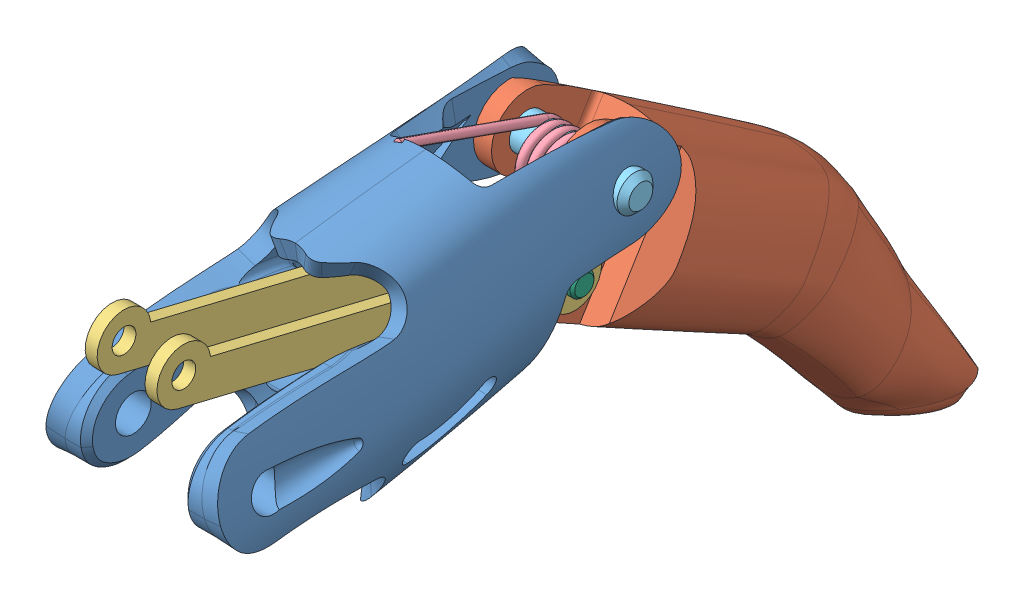
SolidWorks assembly 02-001, configuration 默认. Lengths in mm.
Overall size (17.27 43.69 77.23).
7 component instances, 6 part files, 12 mates.
Components (placement in the parent):
- 01-001-02-1: 01-001-02 [默认] at (7.8667 16.5149 53.1007) x (1 0 0) z (0 -0.162391 0.986726) size (17.27 19.24 40.8)
- 01-002-1: 01-002 [默认] at (7.8667 22.8014 23.7438) x (1 0 0) z (0 0.522694 0.85252) size (12.29 17.46 47.7)
- 01-004-1: 01-004 [默认] at (4.8667 17.742 21.4533) x (-1 0 0) z (0 -0.234701 -0.972068) size (1 6 38.5)
- 01-004-2: 01-004 [默认] at (9.8667 17.742 21.4533) x (-1 0 0) z (0 -0.234701 -0.972068) size (1 6 38.5)
- 01-009-1: 01-009 [默认] at (6.6088 23.9815 18.3511) x (1 0 0) z (0 -0.95607 0.293137) size (5.44 18.26 4.7)
- 01-035-1: 01-035 [默认] at (0.8667 24.547 17.9816) x (0 -0.984187 0.177132) z (-1 0 0) size (3 3 14)
- 01-036-1: 01-036 [默认] at (12.8667 17.2726 19.5091) x (0 -0.458162 -0.888869) z (1 0 0) size (2 2 7.6)
Mates (geometry in assembly coordinates):
- Coincident1: coincident anti-aligned: plane of 01-002-1 through (5.8667 21.8245 20.2373) normal (-1 0 0); plane of 01-004-1 through (5.8667 17.742 21.4533) normal (1 0 0)
- Coincident2: coincident anti-aligned: plane of 01-002-1 through (9.8667 21.8245 20.2373) normal (1 0 0); plane of 01-004-2 through (9.8667 17.742 21.4533) normal (-1 0 0)
- Width1: width anti-aligned: plane of 01-036-1 through (11.6667 16.9061 18.798) normal (1 0 0); plane of 01-002-1 through (4.0667 16.9061 18.798) normal (-1 0 0); plane of 01-036-1 through (5.8667 21.8245 20.2373) normal (-1 0 0); plane of 01-002-1 through (9.8667 21.8245 20.2373) normal (1 0 0)
- Concentric6: concentric aligned: cylinder of 01-004-1 through (5.8667 26.7106 52.2074) axis (-1 0 0) radius 1; cylinder of 01-004-2 through (10.8667 26.7106 52.2074) axis (-1 0 0) radius 1
- Concentric7: concentric aligned: cylinder of 01-002-1 through (7.8717 24.547 17.9816) axis (-1 0 0) radius 3; cylinder of 01-035-1 through (0.8667 24.547 17.9816) axis (-1 0 0) radius 1.5
- Width2: width aligned: plane of 01-035-1 through (0.8667 24.547 17.9816) normal (-1 0 0); plane of 01-002-1 through (14.8667 24.547 17.9816) normal (1 0 0); plane of 01-035-1 through (3.8667 14.7245 28.6959) normal (-1 0 0); plane of 01-002-1 through (11.8667 14.7245 28.6959) normal (1 0 0)
- Concentric8: concentric anti-aligned: cylinder of 01-001-02-1 through (-0.7713 24.547 17.9816) axis (1 0 0) radius 1.5; cylinder of 01-035-1 through (0.8667 24.547 17.9816) axis (-1 0 0) radius 1.5
- Width3: width anti-aligned: plane of 01-001-02-1 through (3.8667 21.0618 52.5699) normal (1 0 0); plane of 01-004-2 through (11.8667 21.0618 52.5699) normal (-1 0 0); plane of 01-001-02-1 through (9.8667 17.742 21.4533) normal (-1 0 0); plane of 01-004-1 through (5.8667 17.742 21.4533) normal (1 0 0)
- Lock1: lock: unknown of 01-002-1; unknown of 01-009-1
- Concentric9: concentric anti-aligned: cylinder of 01-002-1 through (1.6241 17.2726 19.5091) axis (1 0 0) radius 1; cylinder of 01-036-1 through (2.8667 17.2726 19.5091) axis (-1 0 0) radius 1
- Concentric10: concentric aligned: cylinder of 01-004-2 through (10.8667 17.2726 19.5091) axis (-1 0 0) radius 2.25; cylinder of 01-036-1 through (2.8667 17.2726 19.5091) axis (-1 0 0) radius 1
- Concentric11: concentric aligned: cylinder of 01-004-1 through (5.8667 17.2726 19.5091) axis (-1 0 0) radius 2.25; cylinder of 01-036-1 through (2.8667 17.2726 19.5091) axis (-1 0 0) radius 1
